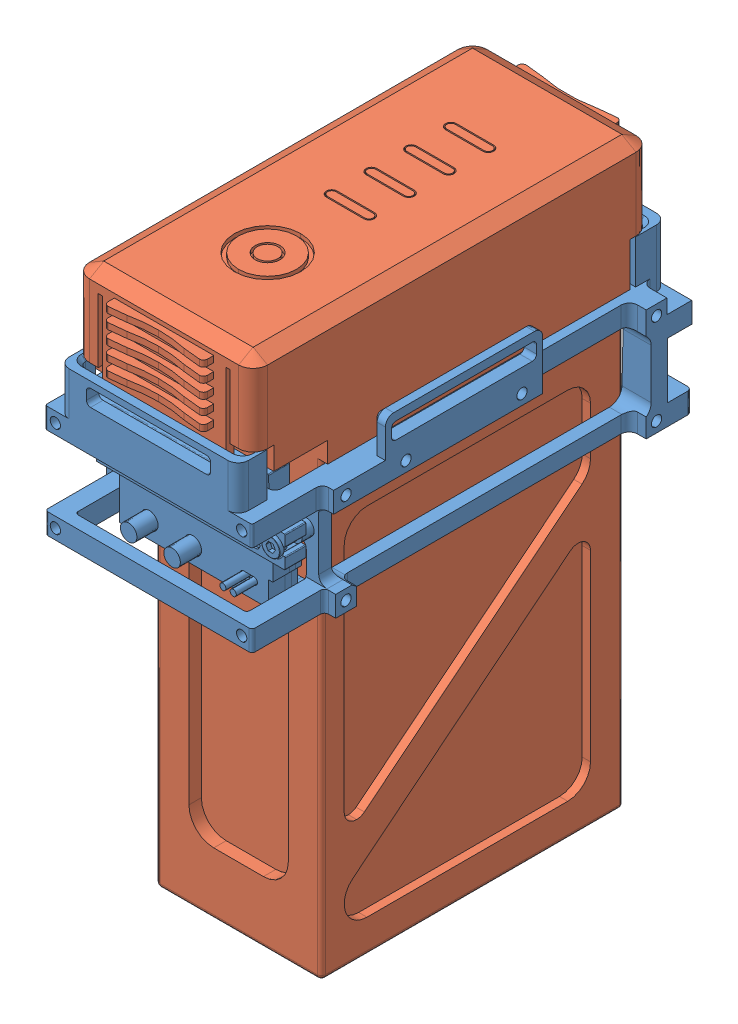
SolidWorks assembly 装配体24, configuration 默认. Lengths in mm.
Overall size (69.4 139 103.5).
2 component instances, 2 part files, 3 mates.
Components (placement in the parent):
- 大疆电池座-2017版-1: 大疆电池座-2017版 [开关位置-默认] at (2.6418 -16.4726 103.5) size (69.4 39.5 103.5)
- TB47d-1: TB47d [默认] at (2.6418 -98.4726 97) x (0 0 -1) z (0 1 0) size (101 43 139)
Mates (geometry in assembly coordinates):
- 宽度1: width: plane of ? through (-18.8582 41.5274 151.5) normal (-1 0 0); plane of ? through (24.1418 41.5274 151.5) normal (1 0 0); plane of 大疆电池座-2017版-1 through (27.6418 -102.3947 139.75) normal (1 0 0); plane of 大疆电池座-2017版-1 through (-22.3582 -102.3947 139.75) normal (-1 0 0)
- 宽度2: width: plane of ? through (24.1418 41.5274 55.5) normal (0 0 -1); plane of ? through (24.1418 41.5274 151.5) normal (0 0 1); plane of 大疆电池座-2017版-1 through (-25.0582 21.0274 155.25) normal (0 0 1); plane of 大疆电池座-2017版-1 through (-25.0582 21.0274 51.75) normal (0 0 -1)
- 重合1: coincident: plane of assembly; plane of assembly; plane of TB47d-1 through (2.6418 21.0274 97) normal (0 -1 0); plane of 大疆电池座-2017版-1 through (2.6418 21.0274 103.5) normal (0 1 0)
